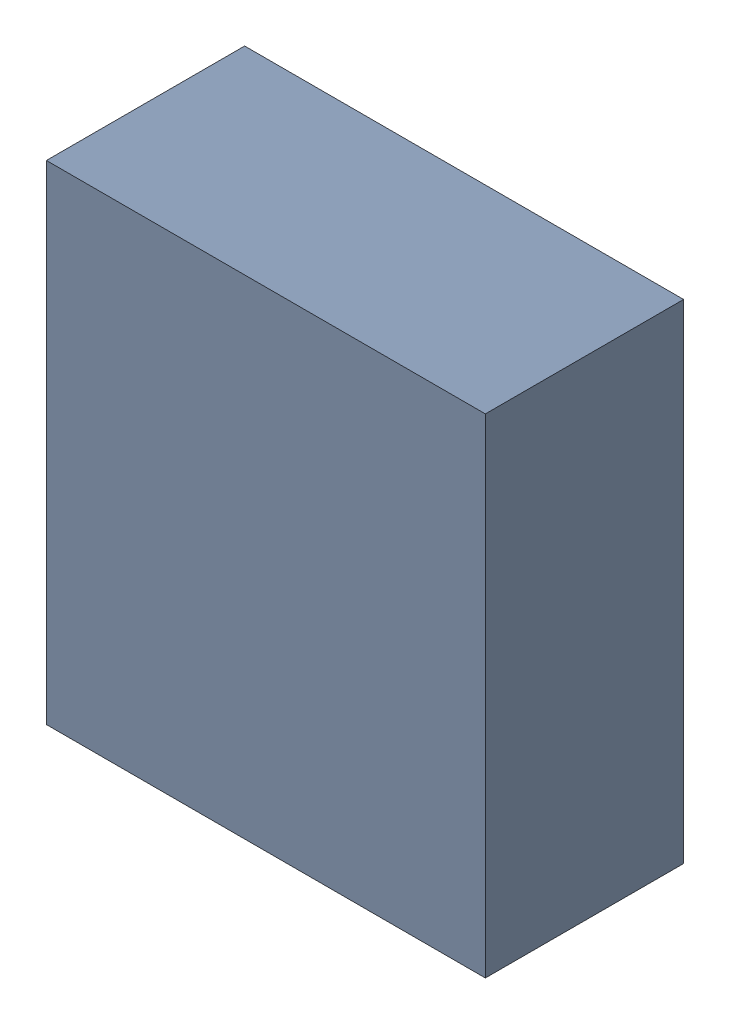
SolidWorks assembly F1_TDA4, configuration Standard. Lengths in mm.
Overall size (3.1 3.45 1.4).
2 component instances, 1 part files, 0 mates.
Components (placement in the parent):
- 885545096-1: 885545096 [Standard] at (3.48 -57.29 0) size (3.1 3.45 1.4)
  - Extruded_5-1: Extruded_5 [Standard] at origin size (3.1 3.45 1.4)
